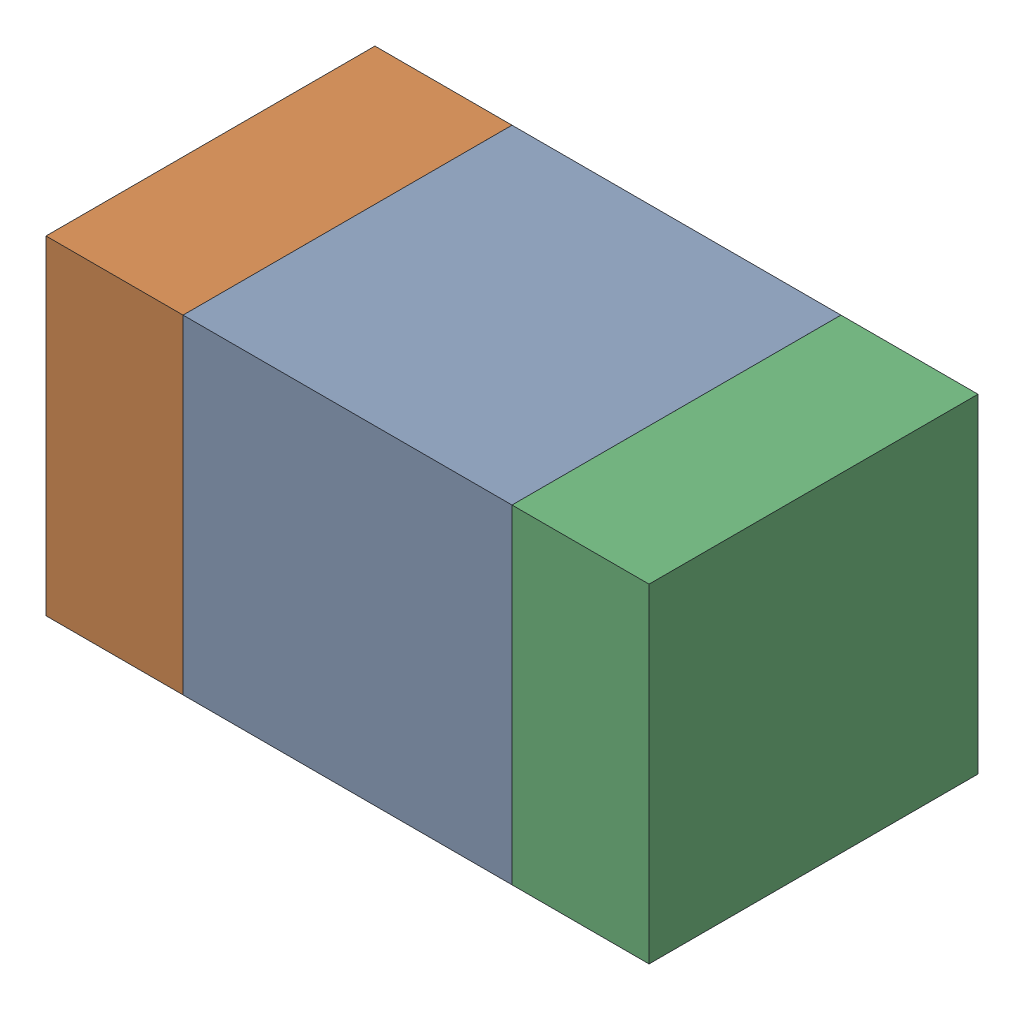
SolidWorks assembly C701PCB, configuration Default. Lengths in mm.
Overall size (1.1 0.6 0.6).
6 component instances, 2 part files, 0 mates.
Components (placement in the parent):
- 761606048-1: 761606048 [Default] at (109.4 114.1 -2.2638) size (0.6 0.6 0.6)
  - Extruded_9-1: Extruded_9 [Default] at origin size (0.6 0.6 0.6)
- 854785160-1: 854785160 [Default] at (108.975 114.1 -2.2638) size (0.25 0.6 0.6)
  - Extruded_19-1: Extruded_19 [Default] at origin size (0.25 0.6 0.6)
- 854785160-2: 854785160 [Default] at (109.825 114.1 -2.2638) size (0.25 0.6 0.6)
  - Extruded_19-1: Extruded_19 [Default] at origin size (0.25 0.6 0.6)
